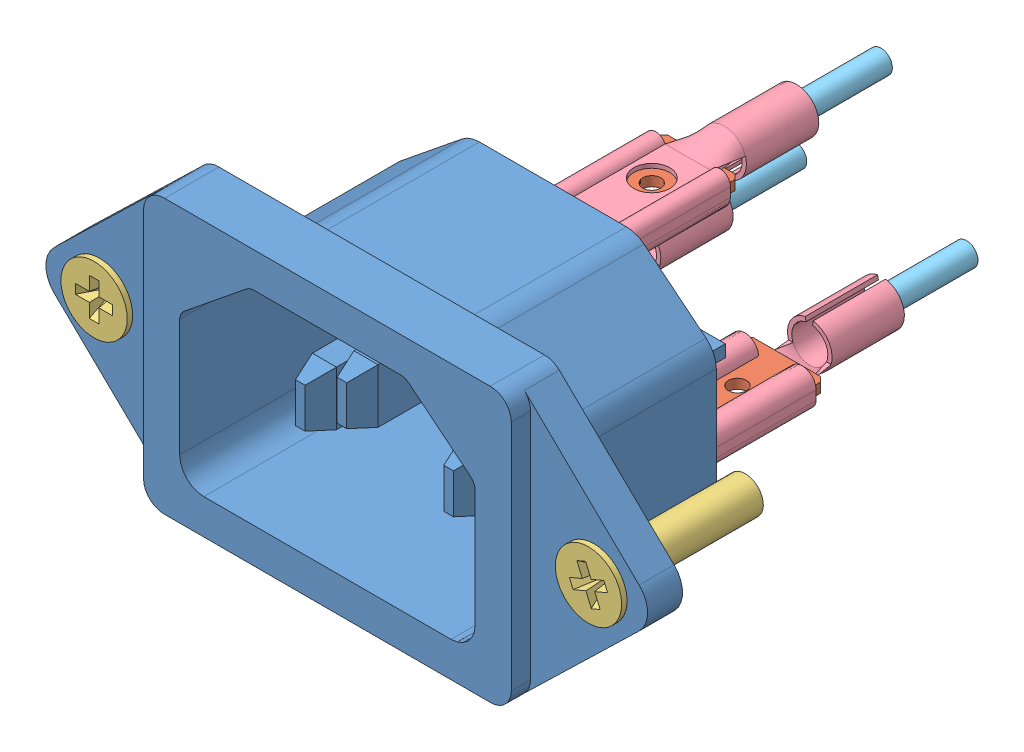
SolidWorks assembly Power Socket Kettle, configuration Default. Lengths in mm.
Overall size (49.9 22.7 48.9).
11 component instances, 5 part files, 19 mates.
Components (placement in the parent):
- Power Socket Kettle-1: Power Socket Kettle [Default] at origin size (49.9 22.7 22.7)
- Solder Tag 1-1: Solder Tag 1 [Default] at (7.1 -6.05 -15.2) x (0 0 1) z (-1 0 0) size (11.3 6.4 6.4)
- Solder Tag 1-3: Solder Tag 1 [Default] at (-7.1 -6.05 -15.2) x (0 0 1) z (-1 0 0) size (11.3 6.4 6.4)
- Solder Tag 1-4: Solder Tag 1 [Default] at (0 5.75 -15.2) x (0 0 1) z (1 0 0) size (11.3 6.4 6.4)
- flat head screw_am-2: flat head screw_am [B18.6.7M - M3 x 0.5 x 13 Type I Cross Recessed FHMS --13N] at (20.5 0 3.35) x (0 0 -1) z (-0.921741 -0.387806 0) size (13 5.5 5.5)
- flat head screw_am-3: flat head screw_am [B18.6.7M - M3 x 0.5 x 13 Type I Cross Recessed FHMS --13N] at (-20.5 0 3.35) x (0 0 -1) z (1 0 0) size (13 5.5 5.5)
- Harness_3-Power Socket Kettle-1: Harness_3-Power Socket Kettle [Default] at origin size (21.25 14.38 29)
  - terminal-1: terminal [Default] at (-7.1 -5.29 -25.4) x (0 -1 0) z (0 0 1) size (3.88 7.05 29)
  - terminal-2: terminal [Default] at (7.1 -5.29 -25.4) x (0 -1 0) z (0 0 1) size (3.88 7.05 29)
  - terminal-3: terminal [Default] at (0 4.99 -25.4) x (0 1 0) z (0 0 1) size (3.88 7.05 29)
  - Cable^Harness_3-Power Socket Kettle-1: Cable^Harness_3-Power Socket Kettle [Default] at origin size (16.1 12.18 7) (virtual)
Mates (geometry in assembly coordinates):
- Coincident1: coincident anti-aligned: plane of Power Socket Kettle-1 through (0 0 -15.2) normal (0 0 -1); plane of Solder Tag 1-1 through (3.9 0.35 -15.2) normal (0 0 1)
- Coincident2: coincident: line of Power Socket Kettle-1 through (-10.3 -6.05 -15.2) axis (1 0 0); plane of Solder Tag 1-1 through (3.9 -6.05 -15.2) normal (0 -1 0)
- Coincident5: coincident anti-aligned: plane of Power Socket Kettle-1 through (0 0 -15.2) normal (0 0 -1); plane of Solder Tag 1-1 through (3.9 0.35 -15.2) normal (0 0 1)
- Parallel2: parallel anti-aligned: line of Power Socket Kettle-1 through (10.3 -6.05 -15.2) axis (-1 0 0); line of Solder Tag 1-1 through (3.9 -6.05 -16.5) axis (1 0 0)
- Coincident7: coincident aligned: line of Power Socket Kettle-1 through (10.3 0.45 -15.2) axis (0 -1 0); line of Solder Tag 1-1 through (10.3 -1.15 -15.2) axis (0 -1 0)
- Coincident12: coincident anti-aligned: plane of Power Socket Kettle-1 through (0 0 -15.2) normal (0 0 -1); plane of Solder Tag 1-3 through (-10.3 0.35 -15.2) normal (0 0 1)
- Coincident13: coincident aligned: line of Power Socket Kettle-1 through (-10.3 0.45 -15.2) axis (0 -1 0); line of Solder Tag 1-3 through (-10.3 -1.15 -15.2) axis (0 -1 0)
- Parallel6: parallel aligned: line of Power Socket Kettle-1 through (-10.3 -6.05 -15.2) axis (1 0 0); line of Solder Tag 1-3 through (-10.3 -6.05 -16.5) axis (1 0 0)
- Coincident16: coincident anti-aligned: plane of Power Socket Kettle-1 through (0 0 -15.2) normal (0 0 -1); plane of Solder Tag 1-4 through (3.2 -0.65 -15.2) normal (0 0 1)
- Coincident17: coincident aligned: line of Solder Tag 1-4 through (3.2 0.85 -15.2) axis (0 1 0); line of Power Socket Kettle-1 through (3.2 0.65 -15.2) axis (0 1 0)
- Parallel7: parallel aligned: line of Power Socket Kettle-1 through (3.2 5.75 -15.2) axis (-1 0 0); line of Solder Tag 1-4 through (3.2 5.75 -16.5) axis (-1 0 0)
- Coincident21: coincident: plane of Power Socket Kettle-1 through (0 0 0) normal (1 0 0); line of Solder Tag 1-4 through (0 -0.65 -16) axis (0 1 0)
- Coincident22: coincident aligned: plane of Power Socket Kettle-1 through (0 -6.05 -15.2) normal (0 -1 0); plane of Solder Tag 1-1 through (3.9 -6.05 -15.2) normal (0 -1 0)
- Coincident23: coincident aligned: plane of Power Socket Kettle-1 through (0 -6.05 -15.2) normal (0 -1 0); plane of Solder Tag 1-3 through (-10.3 -6.05 -15.2) normal (0 -1 0)
- Coincident24: coincident aligned: plane of Power Socket Kettle-1 through (0 5.75 -15.2) normal (0 1 0); plane of Solder Tag 1-4 through (3.2 5.75 -15.2) normal (0 1 0)
- Concentric1: concentric anti-aligned: cylinder of Power Socket Kettle-1 through (20.5 0 2.9) axis (0 0 -1) radius 1.75; cylinder of flat head screw_am-2 through (20.5 0 9.7) axis (0 0 1) radius 1.5
- Coincident27: coincident aligned: cone of Power Socket Kettle-1 through (20.5 0 2.9) axis (0 0 -1); cone of flat head screw_am-2 through (20.5 0 2.9) axis (0 0 -1)
- Concentric2: concentric aligned: cylinder of Power Socket Kettle-1 through (-20.5 0 2.9) axis (0 0 -1) radius 1.75; cone of flat head screw_am-3 through (-20.5 0 2.9) axis (0 0 -1)
- Coincident28: coincident aligned: cone of Power Socket Kettle-1 through (-20.5 0 2.9) axis (0 0 -1); cone of flat head screw_am-3 through (-20.5 0 2.9) axis (0 0 -1)
